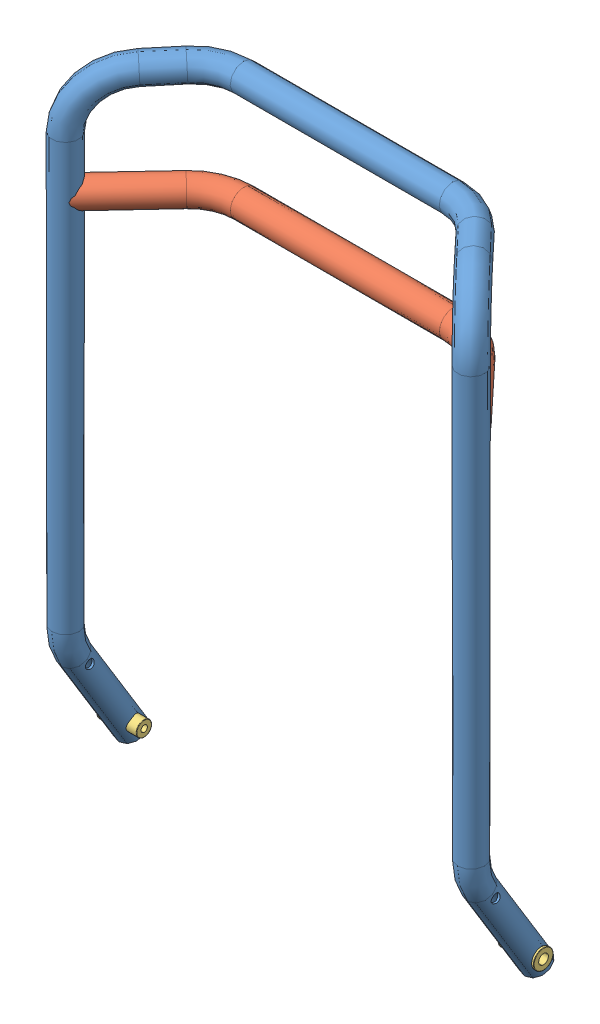
SolidWorks assembly Спинка в сборе (без кронштейна), configuration По умолчанию. Lengths in mm.
Overall size (402.93 576.26 98.9).
4 component instances, 3 part files, 9 mates.
Components (placement in the parent):
- Труба спинки-1-1: Труба спинки-1 [По умолчанию] at origin size (399.91 576.26 98.67)
- Труба спинки-2-1: Труба спинки-2 [По умолчанию] at (186.9661 358.4949 -72.948) x (1 0 0) z (0 0 -1) size (393.57 25 95.02)
- Втулка спинки-1-1: Втулка спинки-1 [По умолчанию] at (-14.5 -85.3105 -52.1739) x (0 0.755748 0.654863) z (1 0 0) size (18 18 35)
- Втулка спинки-1-2: Втулка спинки-1 [По умолчанию] at (388.4322 -85.3105 -52.1739) x (0 0.999965 -0.008388) z (-1 0 0) size (18 18 35)
Mates (geometry in assembly coordinates):
- Совпадение1: coincident aligned: plane of Труба спинки-1-1 through (186.9661 0 0) normal (1 0 0); plane of Труба спинки-2-1 through (186.9661 358.4949 -72.948) normal (1 0 0)
- Совпадение2: coincident aligned: plane of Труба спинки-1-1 through (186.9661 0 0) normal (1 0 0); plane of Труба спинки-2-1 through (186.9661 358.4949 -72.948) normal (1 0 0)
- Касательность3: tangent anti-aligned: cylinder of Труба спинки-2-1 through (283.2826 358.4949 -73.9003) axis (-1 0 0) radius 12.5; plane of Кронштейн спинки-1 through (186.9661 345.9949 -72.948) normal (0 1 0)
- Совпадение3: coincident aligned: plane of Труба спинки-1-1 through (186.9661 0 0) normal (1 0 0); plane of Кронштейн спинки-1 through (186.9661 345.9949 -72.948) normal (1 0 0)
- Расстояние1: distance = 11 mm aligned: plane of Труба спинки-2-1 through (186.9661 358.4949 -72.948) normal (0 0 -1); plane of Кронштейн спинки-1 through (207.4661 340.9949 -83.948) normal (0 0 -1)
- Концентричный7: concentric anti-aligned: cylinder of Труба спинки-1-1 through (-12.5 -85.3105 -52.1739) axis (1 0 0) radius 7.05; cylinder of Втулка спинки-1-1 through (-95.4 -85.3105 -52.1739) axis (-1 0 0) radius 4.5
- Касательность4: tangent anti-aligned: cylinder of Труба спинки-1-1 through (0 -12.0095 -7.3447) axis (0 -0.853105 -0.521739) radius 12.5; plane of Втулка спинки-1-1 through (-12.5 -89.8945 -46.8837) normal (1 0 0)
- Концентричный8: concentric anti-aligned: cylinder of Втулка спинки-1-1 through (-95.4 -85.3105 -52.1739) axis (-1 0 0) radius 7; cylinder of Втулка спинки-1-2 through (469.3322 -85.3105 -52.1739) axis (1 0 0) radius 7
- Касательность5: tangent anti-aligned: cylinder of Труба спинки-1-1 through (373.9322 -12.0095 -7.3447) axis (0 -0.853105 -0.521739) radius 12.5; plane of Втулка спинки-1-2 through (386.4322 -85.3692 -59.1737) normal (-1 0 0)
